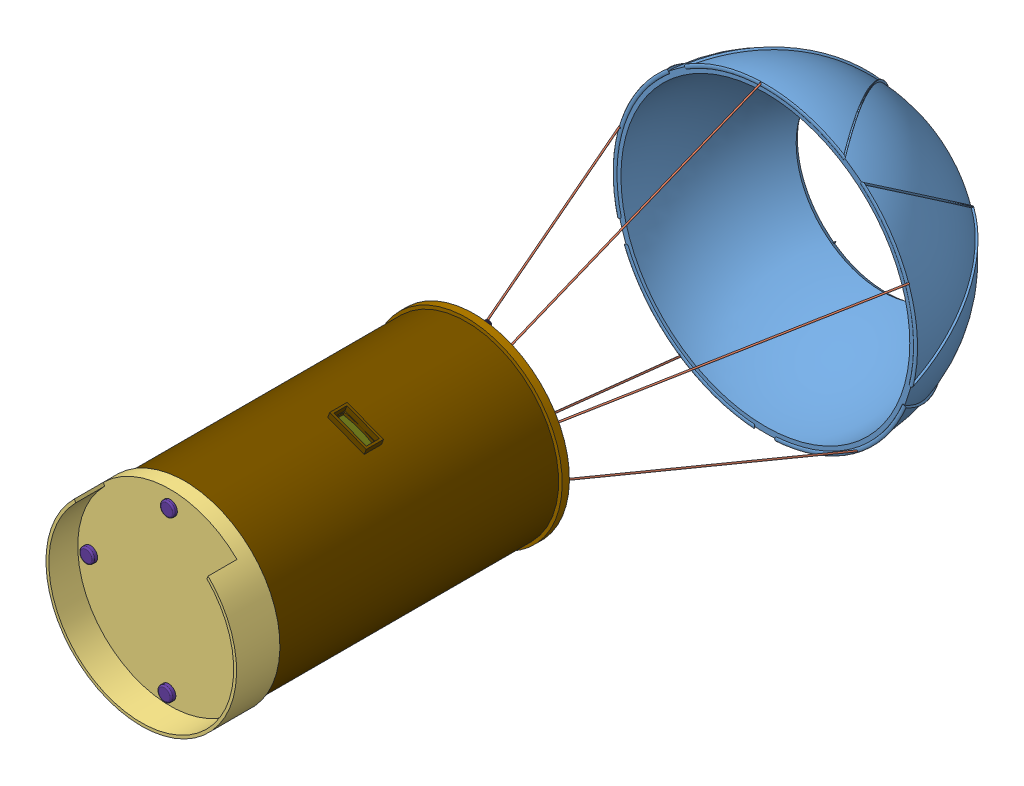
SolidWorks assembly Cansat & Parachute, configuration Default. Lengths in mm.
Overall size (105.79 105.64 258.48).
31 component instances, 18 part files, 10 mates.
Components (placement in the parent):
- Parachute Part1-1: Parachute Part1 [Default] at (32.574 43.9641 92.4892) size (105.79 105.64 45.42)
- Parachute Part2-1: Parachute Part2 [Default] at (31.0622 96.2139 92.3436) x (0.346847 0.880687 0.322627) z (0.937672 -0.317667 -0.14092) size (0.5 150 0.5)
- Parachute Part2-2: Parachute Part2 [Default] at (-18.0389 58.4547 92.3958) x (-0.011067 -0.994694 -0.102279) z (-0.937234 -0.025333 0.347779) size (0.5 150 0.5)
- Parachute Part2-3: Parachute Part2 [Default] at (3.1441 0.3043 92.3944) x (-0.931891 0.348856 0.099396) z (0.297591 0.89194 -0.340416) size (0.5 150 0.5)
- Parachute Part2-4: Parachute Part2 [Default] at (64.5102 2.5812 92.3402) x (-0.815652 -0.578506 -0.006511) z (-0.542593 0.768825 -0.33838) size (0.5 150 0.5)
- Parachute Part2-5: Parachute Part2 [Default] at (82.2785 61.6938 92.4426) x (0.584562 -0.805793 0.094789) z (-0.745349 -0.579487 -0.329621) size (0.5 150 0.5)
- Cansat-1: Cansat [Default] at (7.9482 -13.4135 325.3318) x (1 0 0) z (0 1 0) size (83.27 135.3 84.43)
  - Base-2: Base [Default] at (23.4108 17.9988 57.3834) size (66 15 66)
  - Antenna (GPS)-2: Antenna (GPS) [Default] at (30.0714 112.2022 46.6837) x (0.996195 0 -0.087156) z (0.087156 0 0.996195) size (15 4 15)
  - Antenna (RF)-2: Antenna (RF) [Default] at (9.0622 114.4522 75.2659) x (-0.043619 0 -0.999048) z (0.999048 0 -0.043619) size (6 6.93 10.5)
  - Arduino nano-2: Arduino nano [Default] at (32.1803 60.1363 58.2) x (-0.078459 0 -0.996917) z (0.996917 0 -0.078459) size (47.5 6 18)
  - Battery-1: Battery [Default] at (9.4042 30.4988 65.2261) size (48 15 25)
  - BMP-1: BMP [Default] at (13.6843 59.1363 40.6308) size (10 2 13)
  - Cover-1: Cover [Default] at (23.4108 130.725 57.3834) size (66 2.5 66)
  - DHT11-1: DHT11 [Default] at (13.7282 60.1363 65.3313) x (0.996917 0 -0.078459) z (0.078459 0 0.996917) size (19 6.5 29)
  - GPS-1: GPS [Default] at (31.117 112.2022 45.1384) x (-0.998135 0 0.061049) z (-0.061049 0 -0.998135) size (30 2.5 20)
  - HC-12 (RF)-1: HC-12 (RF) [Default] at (28.385 113.2022 71.6201) x (-0.99863 0 0.052336) z (-0.052336 0 -0.99863) size (27.8 3 14.4)
  - Hook-1: Hook [Default] at (27.1573 141.8384 57.9698) x (0.987972 0 0.15463) z (0 1 0) size (11.16 2.66 19.96)
  - MPU-1: MPU [Default] at (21.9564 86.6691 55.8028) size (20.3 2 15.6)
  - Nut-1: Nut [Default] at (-4.0892 135.5545 57.3834) x (0.998207 0 0.059858) z (-0.059858 0 0.998207) size (3.5 2 4.44)
  - Nut-2: Nut [Default] at (23.4108 135.6141 84.8834) x (0.978775 0 -0.204935) z (0.204935 0 0.978775) size (3.5 2 4.44)
  - Nut-3: Nut [Default] at (50.9108 135.2538 57.3834) x (0.997746 0 0.067106) z (-0.067106 0 0.997746) size (3.5 2 4.44)
  - Nut-4: Nut [Default] at (23.4108 135.1712 29.8834) x (0.63757 0 -0.770392) z (0.770392 0 0.63757) size (3.5 2 4.44)
  - PCB-2: PCB [Default] at (23.4108 83.6691 57.3834) x (0 0 1) z (-1 0 0) size (60 3 60)
  - PCB-3: PCB [Default] at (23.4108 56.1363 57.3834) x (0 0 1) z (-1 0 0) size (60 3 60)
  - PCB-4: PCB [Default] at (23.4108 109.2022 57.3834) x (0 0 1) z (-1 0 0) size (60 3 60)
  - Rod-1: Rod [Default] at (23.4108 28.3245 84.8834) x (0.51847 0 -0.855096) z (0.855096 0 0.51847) size (5 111.5 5)
  - Rod-2: Rod [Default] at (50.9108 27.4561 57.3834) x (-0.908631 0 0.4176) z (-0.4176 0 -0.908631) size (5 111.5 5)
  - Rod-5: Rod [Default] at (23.4108 27.4692 29.8834) x (-0.966748 0 -0.255729) z (0.255729 0 -0.966748) size (5 111.5 5)
  - Rod-6: Rod [Default] at (-4.0892 27.8938 57.3834) x (-0.160074 0 -0.987105) z (0.987105 0 -0.160074) size (5 111.5 5)
  - Body-2: Body [Default] at (23.4108 30.4988 57.3834) x (0.934829 0 -0.3551) z (0.3551 0 0.934829) size (64 100 66)
Mates (geometry in assembly coordinates):
- Tangent3: tangent: curve of Parachute Part1-1; circle of Parachute Part2-1
- Tangent4: tangent: curve of Parachute Part1-1; circle of Parachute Part2-2
- Tangent5: tangent: curve of Parachute Part1-1; circle of Parachute Part2-3
- Tangent6: tangent: curve of Parachute Part1-1; circle of Parachute Part2-4
- Tangent7: tangent: curve of Parachute Part1-1; circle of Parachute Part2-5
- Lock8: lock: unknown of Parachute Part2-5; unknown of Cansat-1/Cover-1
- Lock9: lock: unknown of Parachute Part2-1; unknown of Cansat-1/Cover-1
- Lock10: lock: unknown of Parachute Part2-2; unknown of Cansat-1/Cover-1
- Lock11: lock: unknown of Parachute Part2-4; unknown of Cansat-1/Cover-1
- Lock12: lock: unknown of Parachute Part2-3; unknown of Cansat-1/Cover-1
